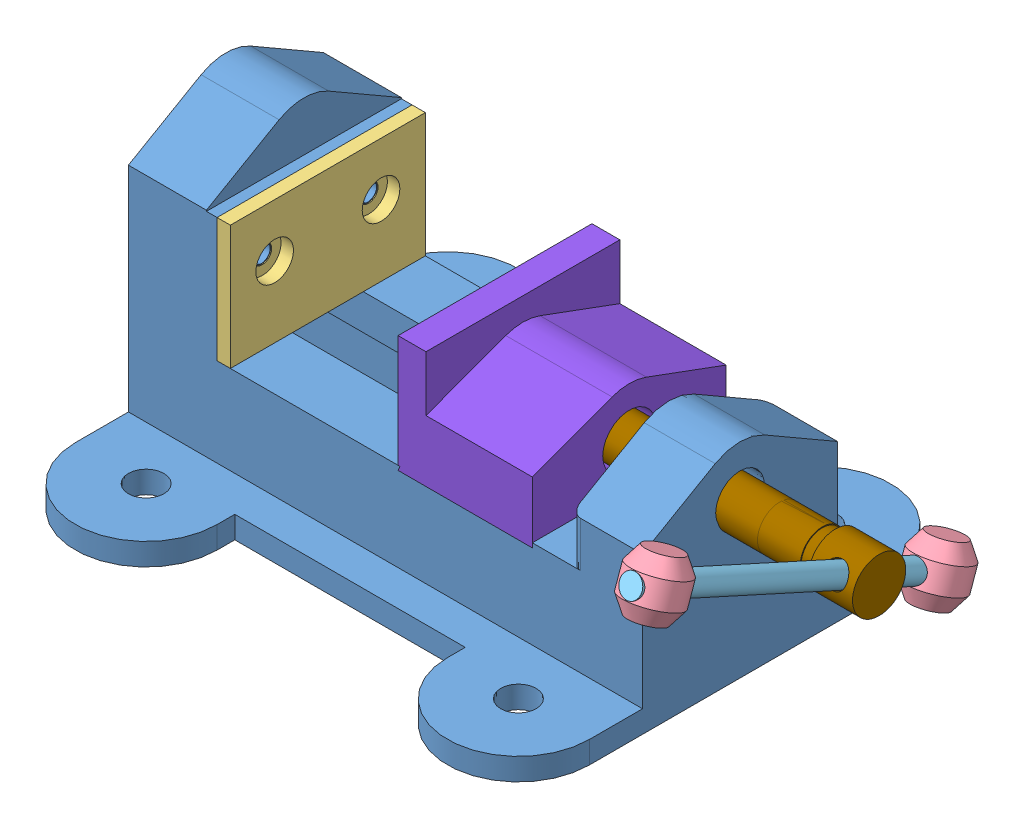
SolidWorks assembly Assem1, configuration Default. Lengths in mm.
Overall size (237.22 101.92 165.61).
11 component instances, 9 part files, 24 mates.
Components (placement in the parent):
- BASE-1: BASE [Default] at (0 0 15.875) size (184.15 101.92 158.75)
- Collar-1: Collar [Default] at (119.3487 53.9614 16.075) x (0 0.998452 0.055629) z (-1 0 0) size (18.26 18.26 20.64)
- FlatJawPlate-1: FlatJawPlate [Default] at (31.75 0 15.875) x (0 0 -1) z (1 0 0) size (69.85 44.45 4.76)
- handle_ball-1: handle_ball [Default] at (227.0727 87.1669 89.2417) x (0.997673 0.062087 -0.028177) z (0 0.413265 0.910611) size (19.05 19.05 19.05)
- handle_rod-1: handle_rod [Default] at (227.0727 64.2049 38.6459) x (0.997673 0.062087 -0.028177) z (0 0.413265 0.910611) size (7.94 7.94 130.18)
- Lock_Screw-1: Lock_Screw [Default] at (95.8996 53.9614 16.075) x (0 0 -1) z (1 0 0) size (16.79 18.26 3.17)
- Slide_Key-1: Slide_Key [Default] at (85.9478 20.6502 9.0868) x (1 0 0) z (0 1 0) size (58.74 8.64 4.7)
- SlidingJaw-1: SlidingJaw [Default] at (144.6853 0 16.075) x (0 0 -1) z (1 0 0) size (69.45 79.91 61.91)
- vice_screw-1: vice_screw [Default] at (234.181 53.9614 16.075) x (-1 0 0) z (0 0.671956 0.740591) size (142.32 19.05 19.05)
- handle_ball-2: handle_ball [Default] at (227.0727 41.2428 -11.9499) x (0.997673 0.062087 -0.028177) z (0 0.413265 0.910611) size (19.05 19.05 19.05)
- Slide_Key-2: Slide_Key [Default] at (85.9478 25.3492 23.0632) x (1 0 0) z (0 -1 0) size (58.74 8.64 4.7)
Mates (geometry in assembly coordinates):
- Coincident1: coincident: point of BASE-1
- Coincident2: coincident anti-aligned: plane of BASE-1 through (0 0 50.8) normal (0 -1 0)
- Coincident3: coincident anti-aligned: plane of BASE-1 through (0 0 50.8) normal (-1 0 0)
- Coincident4: coincident anti-aligned: plane of BASE-1 through (31.75 39.6875 -19.05) normal (1 0 0); plane of FlatJawPlate-1 through (31.75 84.1375 -19.05) normal (-1 0 0)
- Concentric1: concentric aligned: circle of BASE-1; circle of FlatJawPlate-1
- Concentric2: concentric aligned: cylinder of handle_rod-1 through (227.0727 91.1032 97.9153) axis (0 -0.413265 -0.910611) radius 3.9688; cylinder of handle_ball-2 through (227.0727 45.1792 -3.2763) axis (0 -0.413265 -0.910611) radius 3.9688
- Tangent1: tangent: curve of handle_rod-1; curve of handle_ball-2
- Concentric3: concentric aligned: cylinder of handle_ball-1 through (227.0727 91.1032 97.9153) axis (0 -0.413265 -0.910611) radius 3.9688; cylinder of handle_rod-1 through (227.0727 91.1032 97.9153) axis (0 -0.413265 -0.910611) radius 3.9688
- Tangent2: tangent: curve of handle_ball-1; circle of handle_rod-1
- Concentric4: concentric anti-aligned: cylinder of handle_rod-1 through (227.0727 91.1032 97.9153) axis (0 -0.413265 -0.910611) radius 3.9688; cylinder of vice_screw-1 through (227.0727 57.8978 24.7486) axis (0 0.413265 0.910611) radius 4.3663
- Concentric5: concentric anti-aligned: cylinder of Collar-1 through (98.7112 53.9614 16.075) axis (1 0 0) radius 6.5484; cylinder of vice_screw-1 through (91.8587 53.9614 16.075) axis (-1 0 0) radius 6.35
- Coincident5: coincident aligned: plane of handle_ball-1 through (227.0727 87.1669 89.2417) normal (0.997673 0.062087 -0.028177); plane of handle_rod-1 through (227.0727 64.2049 38.6459) normal (0.997673 0.062087 -0.028177)
- Coincident6: coincident aligned: plane of handle_rod-1 through (227.0727 64.2049 38.6459) normal (0.997673 0.062087 -0.028177); plane of handle_ball-2 through (227.0727 41.2428 -11.9499) normal (0.997673 0.062087 -0.028177)
- Concentric6: concentric anti-aligned: cylinder of SlidingJaw-1 through (114.5228 53.9614 16.075) axis (1 0 0) radius 9.525; cylinder of vice_screw-1 through (91.8587 53.9614 16.075) axis (-1 0 0) radius 6.35
- Concentric7: concentric aligned: cylinder of Lock_Screw-1 through (99.0746 53.9614 16.075) axis (-1 0 0) radius 4.9609; cylinder of vice_screw-1 through (91.8587 53.9614 16.075) axis (-1 0 0) radius 4.7336
- Coincident7: coincident anti-aligned: plane of Lock_Screw-1 through (95.8996 53.9614 16.075) normal (-1 0 0); plane of vice_screw-1 through (95.8996 50.4558 19.2558) normal (1 0 0)
- Coincident8: coincident aligned: plane of BASE-1 through (0 0 50.8) normal (0 -1 0); plane of SlidingJaw-1 through (106.5853 0 3.575) normal (0 -1 0)
- Coincident9: coincident anti-aligned: plane of BASE-1 through (0 26.9875 28.575) normal (0 0 -1); plane of SlidingJaw-1 through (106.5853 25.4 28.575) normal (0 0 1)
- Coincident10: coincident anti-aligned: plane of SlidingJaw-1 through (106.5853 20.6502 23.0632) normal (0 0 1); plane of Slide_Key-2 through (85.9478 20.6502 23.0632) normal (0 0 -1)
- Coincident11: coincident anti-aligned: plane of SlidingJaw-1 through (106.5853 20.6502 28.575) normal (0 1 0); plane of Slide_Key-2 through (85.9478 20.6502 31.6992) normal (0 -1 0)
- Coincident13: coincident aligned: plane of SlidingJaw-1 through (144.6853 49.5066 -18.65) normal (1 0 0); plane of Slide_Key-2 through (144.6853 20.6502 23.0632) normal (1 0 0)
- Coincident14: coincident anti-aligned: plane of Slide_Key-1 through (85.9478 25.3492 9.0868) normal (0 0 1); plane of SlidingJaw-1 through (106.5853 20.6502 9.0868) normal (0 0 -1)
- Coincident15: coincident aligned: plane of Slide_Key-1 through (144.6853 25.3492 9.0868) normal (1 0 0); plane of SlidingJaw-1 through (144.6853 49.5066 -18.65) normal (1 0 0)
- Coincident16: coincident anti-aligned: plane of Slide_Key-1 through (85.9478 20.6502 0.4508) normal (0 -1 0); plane of SlidingJaw-1 through (106.5853 20.6502 3.575) normal (0 1 0)
